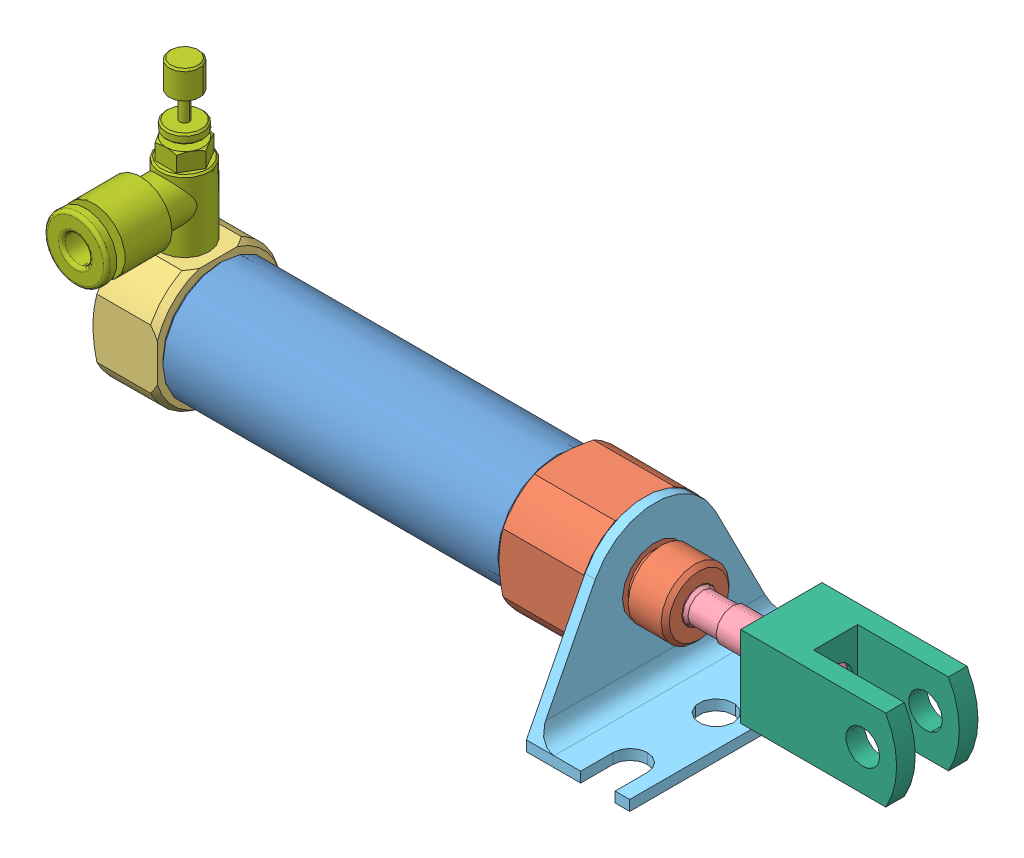
SolidWorks assembly AirCylinder, configuration Default. Lengths in mm.
Overall size (115.7 46.02 34.92).
9 component instances, 7 part files, 6 mates.
Components (placement in the parent):
- NCJ22005Z-MP-1: NCJ22005Z-MP [Default] x (0 0 -1) z (1 0 0) size (34.92 23.88 100.4)
  - NCJ2Tubes-1: NCJ2Tubes [16] at origin size (17.4 17.4 50.4)
  - NCJ2RodCover-1: NCJ2RodCover [16] at (0 0 25.2) size (18 18 20.5)
  - NCJ2HeadCover-1: NCJ2HeadCover [16] at (0 0 -34.7) size (18 18 9.5)
  - NCJ2Rods-1: NCJ2Rods [16] at (0 0 -12.7) size (15.5 15.5 80.9)
  - pneumatic-cylinder-bracket-1: pneumatic-cylinder-bracket [Default] at (0 -13.97 37.7) size (34.92 23.88 15.24)
- RodClevis-1: RodClevis [Default] at (75.85 0 0) size (23 12 12)
- As3054-1: As3054 [Default] at (-30.2 15.45 0) x (0 0 -1) z (1 0 0) size (19.7 26.6 9.3)
  - AS3054 Body-1: AS3054 Body [12-M3-04] at origin size (19.7 26.6 9.3)
Mates (geometry in assembly coordinates):
- Concentric1: concentric anti-aligned: cylinder of NCJ22005Z-MP-1/NCJ2HeadCover-1 through (-30.2 4 0) axis (0 1 0) radius 2.5; cylinder of As3054-1/AS3054 Body-1 through (-30.2 19.45 0) axis (0 -1 0) radius 3.6
- Coincident1: coincident aligned: plane of NCJ22005Z-MP-1/NCJ2RodCover-1 through (37.7 9 4.3589) normal (0 1 0); circle of As3054-1/AS3054 Body-1
- Parallel2: parallel aligned: plane of NCJ22005Z-MP-1; plane of As3054-1
- Concentric2: concentric aligned: cylinder of NCJ22005Z-MP-1/NCJ2Rods-1 through (65.7 0 0) axis (-1 0 0) radius 2.5; cylinder of RodClevis-1 through (68.85 0 0) axis (-1 0 0) radius 2.5
- Distance1: distance = 0.15 mm aligned: plane of NCJ22005Z-MP-1/NCJ2Rods-1 through (65.7 0 0) normal (1 0 0); plane of RodClevis-1 through (65.85 -6 3.25) normal (1 0 0)
- Parallel3: parallel aligned: plane of NCJ22005Z-MP-1/pneumatic-cylinder-bracket-1 through (52.94 -12.446 17.4625) normal (0 1 0); plane of RodClevis-1 through (57.85 6 6) normal (0 1 0)
